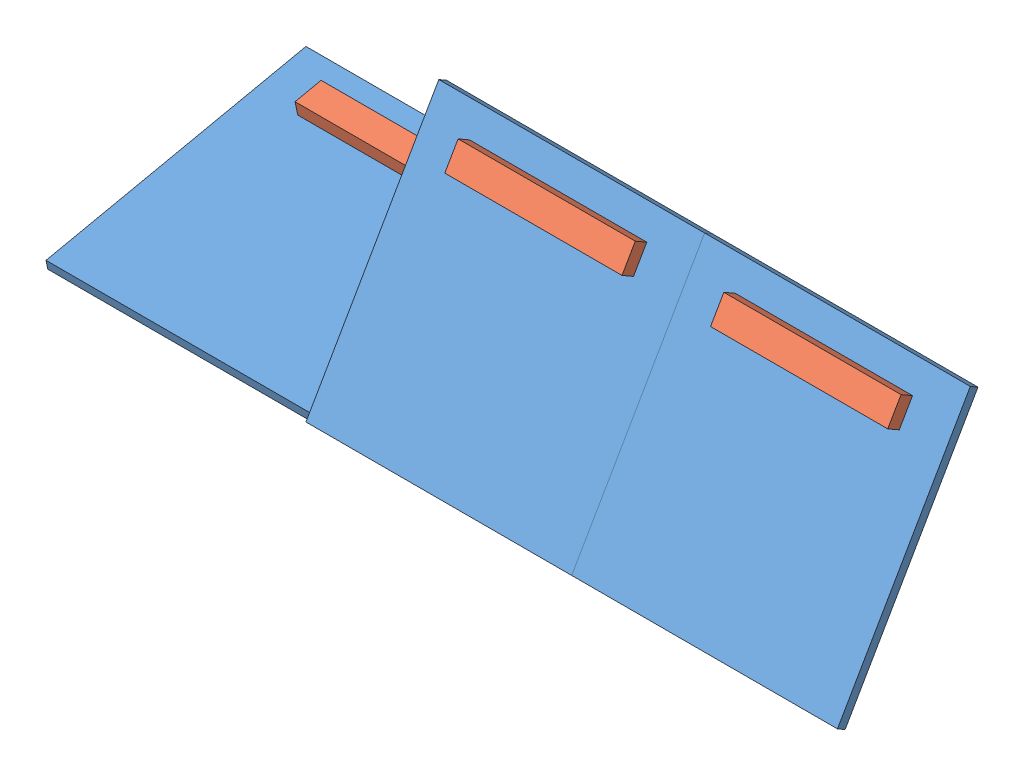
SolidWorks assembly TestSetup, configuration Default. Lengths in mm.
Overall size (9000 2648.08 3021.05).
6 component instances, 2 part files, 20 mates.
Components (placement in the parent):
- Ground-1: Ground [Default] at (-1500 311.8675 -1467.2214) x (1 0 0) z (0 -0.207912 0.978148) size (3000 100 3000)
- Ground-2: Ground [Default] at (1500 1299.0381 -750) x (1 0 0) z (0 -0.866025 0.5) size (3000 100 3000)
- Ground-3: Ground [Default] at (4500 1299.0381 -750) x (1 0 0) z (0 -0.866025 0.5) size (3000 100 3000)
- Log-1: Log [Default] at (4500 2291.7079 -1121.0456) x (1 0 0) z (0 -0.866025 0.5) size (2000 150 300)
- Log-2: Log [Default] at (1500 2291.7079 -1121.0456) x (1 0 0) z (0 -0.866025 0.5) size (2000 150 300)
- Log-3: Log [Default] at (-1500 700.3527 -2453.1967) x (1 0 0) z (0 -0.207912 0.978148) size (2000 150 300)
Mates (geometry in assembly coordinates):
- Coincident2: coincident: line of Ground-1 through (0 3000 -3000) axis (0 0 1)
- Coincident3: coincident: line of Ground-1 through (0 0 0) axis (0 0.207912 -0.978148)
- Coincident4: coincident anti-aligned: line of Ground-1 through (0 3000 -3000) axis (0 0 1)
- Angle1: planar angle = 0.20944 rad anti-aligned: plane of Ground-1 through (-1500 311.8675 -1467.2214) normal (0 -0.978148 -0.207912)
- Coincident6: coincident anti-aligned: plane of Ground-1 through (0 97.8148 20.7912) normal (1 0 0); plane of Ground-2 through (0 50 86.6025) normal (-1 0 0)
- Coincident7: coincident: line of Ground-2 through (0 3000 0) axis (0 0 1)
- Coincident8: coincident: line of Ground-2 through (0 3000 0) axis (0 0 1)
- Angle2: planar angle = 1.047198 rad anti-aligned: plane of Ground-2 through (1500 1299.0381 -750) normal (0 -0.5 -0.866025)
- Coincident10: coincident anti-aligned: plane of Ground-2 through (3000 50 86.6025) normal (1 0 0); plane of Ground-3 through (3000 50 86.6025) normal (-1 0 0)
- Coincident11: coincident aligned: line of Ground-2 through (0 3000 0) axis (0 0 1); line of Ground-3 through (0 3000 3000) axis (0 0 1)
- Coincident12: coincident aligned: plane of Ground-2 through (1500 1299.0381 -750) normal (0 -0.5 -0.866025); plane of Ground-3 through (4500 1299.0381 -750) normal (0 -0.5 -0.866025)
- Coincident13: coincident anti-aligned: plane of Ground-3 through (4500 1349.0381 -663.3975) normal (0 0.5 0.866025); plane of Log-1 through (4500 2254.2079 -1185.9975) normal (0 -0.5 -0.866025)
- Width2: width anti-aligned: plane of Ground-3 through (3000 50 86.6025) normal (-1 0 0); plane of Ground-3 through (6000 50 86.6025) normal (1 0 0); plane of Log-1 through (5500 2459.1117 -1131.0936) normal (1 0 0); plane of Log-1 through (3500 2459.1117 -1131.0936) normal (-1 0 0)
- Distance1: distance = 304.8 mm aligned: plane of Log-1 through (3500 2459.1117 -1131.0936) normal (0 0.866025 -0.5); plane of Ground-3 through (3000 2648.0762 -1413.3975) normal (0 0.866025 -0.5)
- Coincident14: coincident anti-aligned: plane of Ground-2 through (1500 1349.0381 -663.3975) normal (0 0.5 0.866025); plane of Log-2 through (1500 2254.2079 -1185.9975) normal (0 -0.5 -0.866025)
- Distance2: distance = 304.8 mm aligned: plane of Log-2 through (500 2459.1117 -1131.0936) normal (0 0.866025 -0.5); plane of Ground-2 through (0 2648.0762 -1413.3975) normal (0 0.866025 -0.5)
- Width3: width anti-aligned: plane of Log-2 through (2500 2459.1117 -1131.0936) normal (1 0 0); plane of Log-2 through (500 2459.1117 -1131.0936) normal (-1 0 0); plane of Ground-2 through (0 50 86.6025) normal (-1 0 0); plane of Ground-2 through (3000 50 86.6025) normal (1 0 0)
- Coincident17: coincident anti-aligned: plane of Ground-1 through (-1500 409.6823 -1446.4302) normal (0 0.978148 0.207912); plane of Log-3 through (-1500 626.9916 -2468.7901) normal (0 -0.978148 -0.207912)
- Distance3: distance = 304.8 mm aligned: plane of Log-3 through (-2500 804.9005 -2584.3255) normal (0 0.207912 -0.978148); plane of Ground-1 through (-3000 721.5498 -2913.6516) normal (0 0.207912 -0.978148)
- Width4: width anti-aligned: plane of Log-3 through (-2500 804.9005 -2584.3255) normal (-1 0 0); plane of Log-3 through (-500 804.9005 -2584.3255) normal (1 0 0); plane of Ground-1 through (0 97.8148 20.7912) normal (1 0 0); plane of Ground-1 through (-3000 97.8148 20.7912) normal (-1 0 0)
